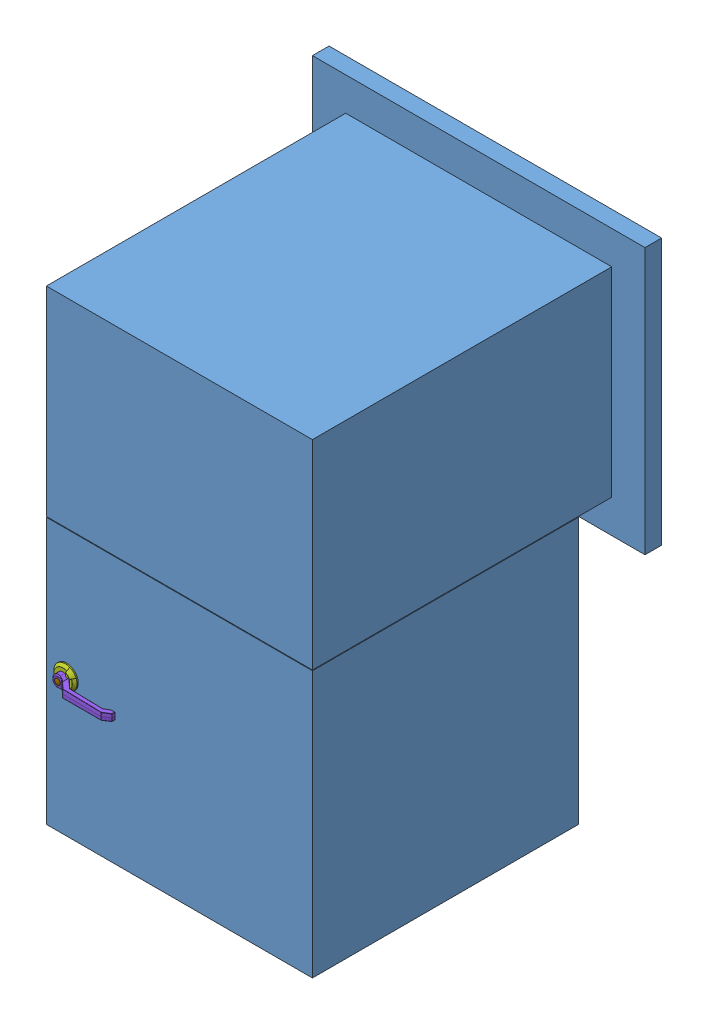
SolidWorks assembly 0TTW, configuration Default. Lengths in mm.
Overall size (1000 1502 1008.5).
10 component instances, 9 part files, 13 mates.
Components (placement in the parent):
- Body-1: Body [Default] at (-79.2601 1362.1524 443.4876) size (1000 1502 950)
- 17inch-1: 17inch [Default] at (665.7399 1568.5625 613.4876) x (-1 0 0) z (0 0 -1) size (340 270 10)
- XST card reader PI65C-120-GDS-MFR-1: XST card reader PI65C-120-GDS-MFR [Default] at (109.8423 1552.9451 407.0276) x (-1 0 0) z (0 0 -1) size (101.6 25.4 105.37)
- thermal printer-1: thermal printer [Default] at (109.3012 1680.2528 466.9876) x (-1 0 0) z (0 0 -1) size (132 144.55 271.2)
- KeypadMetal-1: KeypadMetal [Default] at (492.3701 1430.4606 558.0469) x (-1 0 0) z (0 -0.965926 0.258819) size (133.3 91.1 23.5)
- Ofaly-1: Ofaly [Default] at (536.6447 1992.611 393.4876) x (-0.999999 -0.001354 0) z (0.001354 -0.999999 0) size (200.51 8 62.34)
- Ручка DIDAK-1: Ручка DIDAK [По умолчанию] at (81.5095 975.5889 1343.4876) x (0.707107 0.707107 0) z (0.707107 -0.707107 0) size (169.1 55.2 171.71)
  - Накладка Со Стопором 232-0410.03-1: Накладка Со Стопором 232-0410.03 [По умолчанию] at origin size (70 21.3 70)
  - Ручка 176-1: Ручка 176 [По умолчанию] at (13.4157 30.7 13.7353) x (0.698733 0 0.715383) z (0 -1 0) size (191.5 34.6 51)
  - Заглушка D14 (Черная)-1: Заглушка D14 (Черная) [По умолчанию] at (0 27.39 0) x (0.892078 0 -0.451881) z (0.451881 0 0.892078) size (16.7 8.3 16.7)
Mates (geometry in assembly coordinates):
- Coincident1: coincident anti-aligned: plane of Body-1 through (-79.2601 1362.1524 613.4876) normal (0 0 -1); plane of 17inch-1 through (665.7399 1568.5625 613.4876) normal (0 0 1)
- Coincident2: coincident anti-aligned: plane of Body-1 through (325.7399 1568.5625 613.4876) normal (0 1 0); plane of 17inch-1 through (325.7399 1568.5625 603.4876) normal (0 -1 0)
- Coincident4: coincident anti-aligned: plane of Body-1 through (665.7399 1838.5625 613.4876) normal (-1 0 0); plane of 17inch-1 through (665.7399 1838.5625 603.4876) normal (1 0 0)
- Distance1: distance = 1 mm aligned: plane of Body-1 through (-79.2601 1362.1524 403.4876) normal (0 0 -1); plane of XST card reader PI65C-120-GDS-MFR-1 through (59.0432 1540.2451 404.4876) normal (0 0 -1)
- Parallel1: parallel aligned: plane of Body-1 through (920.7399 2062.1524 443.4876) normal (0 1 0); plane of XST card reader PI65C-120-GDS-MFR-1 through (142.2268 1555.9451 481.9569) normal (0 1 0)
- Distance2: distance = 1 mm aligned: plane of Body-1 through (-79.2601 1362.1524 403.4876) normal (0 0 -1); plane of thermal printer-1 through (109.3012 1738.5528 404.4876) normal (0 0 -1)
- Parallel2: parallel aligned: plane of Body-1 through (920.7399 1262.1524 443.4876) normal (0 -1 0); plane of thermal printer-1 through (109.3012 1680.2528 466.9876) normal (0 -1 0)
- Distance3: distance = 1 mm aligned: plane of KeypadMetal-1 through (492.3701 1432.3924 557.5293) normal (0 0.965926 -0.258819); plane of Body-1 through (790.7399 1392.1524 403.4876) normal (0 0.965926 -0.258819)
- Parallel4: parallel anti-aligned: line of Body-1 through (790.7399 1392.1524 403.4876) axis (-1 0 0); line of KeypadMetal-1 through (443.8701 1433.5349 554.0655) axis (1 0 0)
- Coincident5: coincident anti-aligned: plane of Body-1 through (920.7399 2062.1524 393.4876) normal (0 0 -1); plane of Ofaly-1 through (527.4449 1997.2518 393.4876) normal (0 0 1)
- Parallel5: parallel anti-aligned: plane of Body-1 through (920.7399 2062.1524 443.4876) normal (0 1 0); plane of Ofaly-1 through (470.7624 1992.5523 385.4876) normal (0 -1 0)
- Coincident6: coincident anti-aligned: plane of Body-1 through (920.7399 1360.1524 1343.4876) normal (0 0 1); plane of Ручка DIDAK-1/Накладка Со Стопором 232-0410.03-1 through (81.5095 975.5889 1343.4876) normal (0 0 -1)
- Parallel6: parallel aligned: plane of Body-1 through (920.7399 560.1524 543.4876) normal (0 -1 0); plane of Ручка DIDAK-1/Ручка 176-1 through (100.566 963.2887 1393.9876) normal (0 -1 0)
